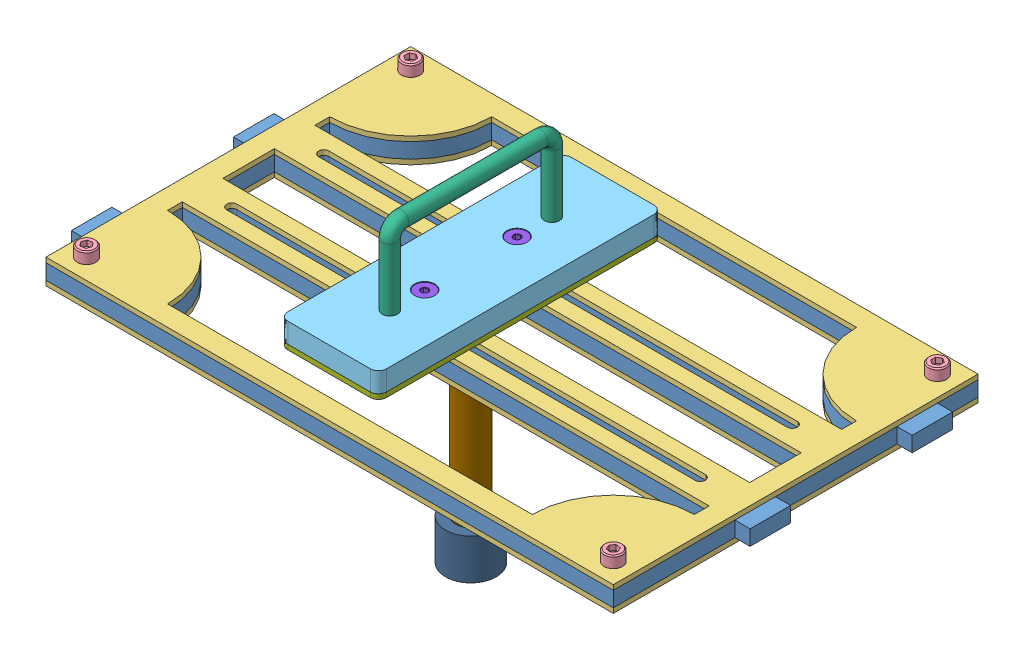
SolidWorks assembly Killswitch4, configuration Default. Lengths in mm.
Overall size (187.33 106.62 114.3).
23 component instances, 11 part files, 39 mates.
Components (placement in the parent):
- Panel-2: Panel [Default] at origin size (187.33 4.76 114.3)
- Magnet-1: Magnet [Default] at (73.406 2.3813 39.37) size (4.76 4.76 4.76)
- Magnet-2: Magnet [Default] at (73.406 2.3813 -39.37) size (4.76 4.76 4.76)
- Magnet-3: Magnet [Default] at (-73.406 2.3813 -39.37) size (4.76 4.76 4.76)
- Magnet-4: Magnet [Default] at (-73.406 2.3813 39.37) size (4.76 4.76 4.76)
- AcrylicPanel-1: AcrylicPanel [Default] at (0 4.7625 0) size (177.8 1.52 114.3)
- AcrylicPanel-2: AcrylicPanel [Default] at (0 -1.524 0) size (177.8 1.52 114.3)
- Socket Head Cap Screw_AI-2: Socket Head Cap Screw_AI [HX-SHCS 0.138-40x0.3125x0.3125-C] at (-82.55 9.7917 -50.8) x (0 -1 0) z (0.436855 0 0.899532) size (11.44 5.74 5.74)
- Socket Head Cap Screw_AI-3: Socket Head Cap Screw_AI [HX-SHCS 0.138-40x0.3125x0.3125-C] at (82.55 9.7917 -50.8) x (0 -1 0) z (-0.495278 0 0.868734) size (11.44 5.74 5.74)
- Socket Head Cap Screw_AI-4: Socket Head Cap Screw_AI [HX-SHCS 0.138-40x0.3125x0.3125-C] at (82.55 9.7917 50.8) x (0 -1 0) z (-0.933448 0 0.358714) size (11.44 5.74 5.74)
- Socket Head Cap Screw_AI-5: Socket Head Cap Screw_AI [HX-SHCS 0.138-40x0.3125x0.3125-C] at (-82.55 9.7917 50.8) x (0 -1 0) z (0.168939 0 0.985627) size (11.44 5.74 5.74)
- Slider-2: Slider [Default] at (-12.8947 12.573 -0.003) x (-1 0 0) z (0 0 1) size (30.96 6.29 88.9)
- Magnet-7: Magnet [Default] at (-12.8947 10.1917 -39.119) size (4.76 4.76 4.76)
- Magnet-8: Magnet [Default] at (-12.8947 10.1917 39.113) size (4.76 4.76 4.76)
- 1568A630-1: 1568A630 [1568A63] at (-12.8947 37.1158 -0.003) x (0 0 1) z (1 0 0) size (55.56 25.63 4.76)
- SliderAcrylic-1: SliderAcrylic [Default] at (-12.8947 6.2865 -0.003) size (30.96 1.52 88.9)
- Socket Head Cap Screw_AI-6: Socket Head Cap Screw_AI [HX-SHCS 0.112-40x0.4375x0.4375-C] at (-12.8947 3.4417 -25.403) x (0 1 0) z (0 0 1) size (13.96 4.65 4.65)
- Socket Head Cap Screw_AI-7: Socket Head Cap Screw_AI [HX-SHCS 0.112-40x0.4375x0.4375-C] at (-12.8947 3.4417 25.397) x (0 1 0) z (-0.253818 0 0.967252) size (13.96 4.65 4.65)
- 97345A428-3: 97345A428 [97345A428] at (-12.8947 10.795 14.475) size (6.35 20.18 6.35)
- 97345A428-4: 97345A428 [97345A428] at (-12.8947 10.795 -14.481) size (6.35 20.18 6.35)
- MagnetHolderB-1: MagnetHolderB [Default] at (-12.8947 -27.4955 -0.003) x (0.135705 0 0.990749) z (-0.990749 0 0.135705) size (9.53 76.2 9.53)
- MagnetCapAcrylic-1: MagnetCapAcrylic [Default] at (-12.8947 -67.1195 -0.003) x (0.50888 0 0.860837) z (-0.860837 0 0.50888) size (15.88 12.7 15.88)
- BigMagnet-1: BigMagnet [Default] at (-12.8947 -65.5955 -0.003) size (6.35 6.35 6.35)
Mates (geometry in assembly coordinates):
- Coincident1: coincident aligned: circle of Panel-2; circle of Magnet-1
- Coincident2: coincident aligned: circle of Panel-2; circle of Magnet-2
- Coincident3: coincident aligned: circle of Panel-2; circle of Magnet-4
- Coincident4: coincident aligned: circle of Panel-2; circle of Magnet-3
- Coincident5: coincident aligned: line of Panel-2 through (82.55 4.7625 -20.7675) axis (-1 0 0); line of AcrylicPanel-1 through (82.55 4.7625 -20.7675) axis (-1 0 0)
- Concentric1: concentric aligned: circle of Panel-2; circle of AcrylicPanel-1
- Coincident7: coincident aligned: line of Panel-2 through (82.55 0 -20.7675) axis (-1 0 0); line of AcrylicPanel-2 through (82.55 0 -20.7675) axis (-1 0 0)
- Concentric2: concentric aligned: circle of Panel-2; circle of AcrylicPanel-2
- Concentric81: concentric aligned: cylinder of Panel-2 through (-82.55 6.2865 -50.8) axis (0 1 0) radius 1.3526; cylinder of Socket Head Cap Screw_AI-2 through (-82.55 41.5417 -50.8) axis (0 1 0) radius 2.8702
- Concentric91: concentric aligned: cylinder of Panel-2 through (82.55 6.2865 -50.8) axis (0 1 0) radius 1.3526; cylinder of Socket Head Cap Screw_AI-3 through (82.55 41.5417 -50.8) axis (0 1 0) radius 2.8702
- Concentric101: concentric aligned: cylinder of Panel-2 through (82.55 6.2865 50.8) axis (0 1 0) radius 1.3526; cylinder of Socket Head Cap Screw_AI-4 through (82.55 41.5417 50.8) axis (0 1 0) radius 2.8702
- Concentric111: concentric aligned: cylinder of Panel-2 through (-82.55 6.2865 50.8) axis (0 1 0) radius 1.3526; cylinder of Socket Head Cap Screw_AI-5 through (-82.55 41.5417 50.8) axis (0 1 0) radius 2.8702
- Coincident25: coincident anti-aligned: plane of AcrylicPanel-1 through (-164.5488 6.2865 0) normal (0 1 0); plane of Socket Head Cap Screw_AI-5 through (-79.7211 6.2865 50.3151) normal (0 -1 0)
- Coincident26: coincident anti-aligned: plane of AcrylicPanel-1 through (-164.5488 6.2865 0) normal (0 1 0); plane of Socket Head Cap Screw_AI-2 through (-79.9682 6.2865 -52.0539) normal (0 -1 0)
- Coincident27: coincident anti-aligned: plane of AcrylicPanel-1 through (-164.5488 6.2865 0) normal (0 1 0); plane of Socket Head Cap Screw_AI-4 through (83.5796 6.2865 53.4792) normal (0 -1 0)
- Coincident28: coincident anti-aligned: plane of AcrylicPanel-1 through (-164.5488 6.2865 0) normal (0 1 0); plane of Socket Head Cap Screw_AI-3 through (85.0434 6.2865 -49.3785) normal (0 -1 0)
- Tangent1: tangent anti-aligned: plane of Panel-2 through (-73.406 0 -16.005) normal (0 0 1); cylinder of Slider-2 through (-12.8947 7.8105 -14.481) axis (0 1 0) radius 1.524
- Parallel1: parallel aligned: plane of Panel-2 through (-164.5488 4.7625 57.15) normal (0 0 1); plane of Slider-2 through (2.5834 7.8105 44.447) normal (0 0 1)
- Coincident36: coincident aligned: circle of Slider-2; circle of Magnet-7
- Coincident37: coincident aligned: circle of Slider-2; circle of Magnet-8
- Concentric13: concentric aligned: circle of Slider-2; circle of 1568A630-1
- Concentric14: concentric anti-aligned: circle of Slider-2; circle of 1568A630-1
- Coincident38: coincident anti-aligned: plane of Slider-2 through (-25.8329 14.097 -41.913) normal (0 1 0); plane of 1568A630-1 through (-12.8947 14.097 25.397) normal (0 -1 0)
- Coincident39: coincident anti-aligned: plane of Slider-2 through (-28.3729 7.8105 -44.453) normal (0 -1 0); plane of SliderAcrylic-1 through (2.5834 7.8105 -44.453) normal (0 1 0)
- Concentric15: concentric anti-aligned: circle of Slider-2; circle of SliderAcrylic-1
- Coincident41: coincident anti-aligned: plane of AcrylicPanel-1 through (-164.5488 6.2865 0) normal (0 1 0); plane of SliderAcrylic-1 through (2.5834 6.2865 -44.453) normal (0 -1 0)
- Concentric16: concentric aligned: circle of Slider-2; circle of Socket Head Cap Screw_AI-7
- Coincident44: coincident anti-aligned: plane of SliderAcrylic-1 through (2.5834 6.2865 -44.453) normal (0 -1 0); plane of Socket Head Cap Screw_AI-7 through (-15.1427 6.2865 24.8071) normal (0 1 0)
- Concentric17: concentric aligned: circle of Slider-2; circle of Socket Head Cap Screw_AI-6
- Coincident45: coincident anti-aligned: plane of SliderAcrylic-1 through (2.5834 6.2865 -44.453) normal (0 -1 0); plane of Socket Head Cap Screw_AI-6 through (-15.2188 6.2865 -25.403) normal (0 1 0)
- Concentric22: concentric aligned: circle of Slider-2; circle of 97345A428-3
- Coincident70: coincident anti-aligned: plane of Slider-2 through (-12.8947 10.795 14.475) normal (0 1 0); plane of 97345A428-3 through (-12.8947 10.795 14.475) normal (0 -1 0)
- Concentric23: concentric aligned: circle of Slider-2; circle of 97345A428-4
- Coincident71: coincident anti-aligned: plane of Slider-2 through (-12.8947 10.795 -14.481) normal (0 1 0); plane of 97345A428-4 through (-12.8947 10.795 -14.481) normal (0 -1 0)
- Concentric112: concentric anti-aligned: circle of Slider-2; circle of MagnetHolderB-1
- Coincident72: coincident anti-aligned: circle of Slider-2; plane of MagnetHolderB-1 through (-12.8947 10.6045 -0.003) normal (0 1 0)
- Concentric113: concentric aligned: circle of MagnetHolderB-1; circle of MagnetCapAcrylic-1
- Coincident76: coincident anti-aligned: plane of MagnetHolderB-1 through (-12.8947 -65.5955 -0.003) normal (0 -1 0); circle of MagnetCapAcrylic-1
- Coincident78: coincident anti-aligned: circle of MagnetHolderB-1; circle of BigMagnet-1
